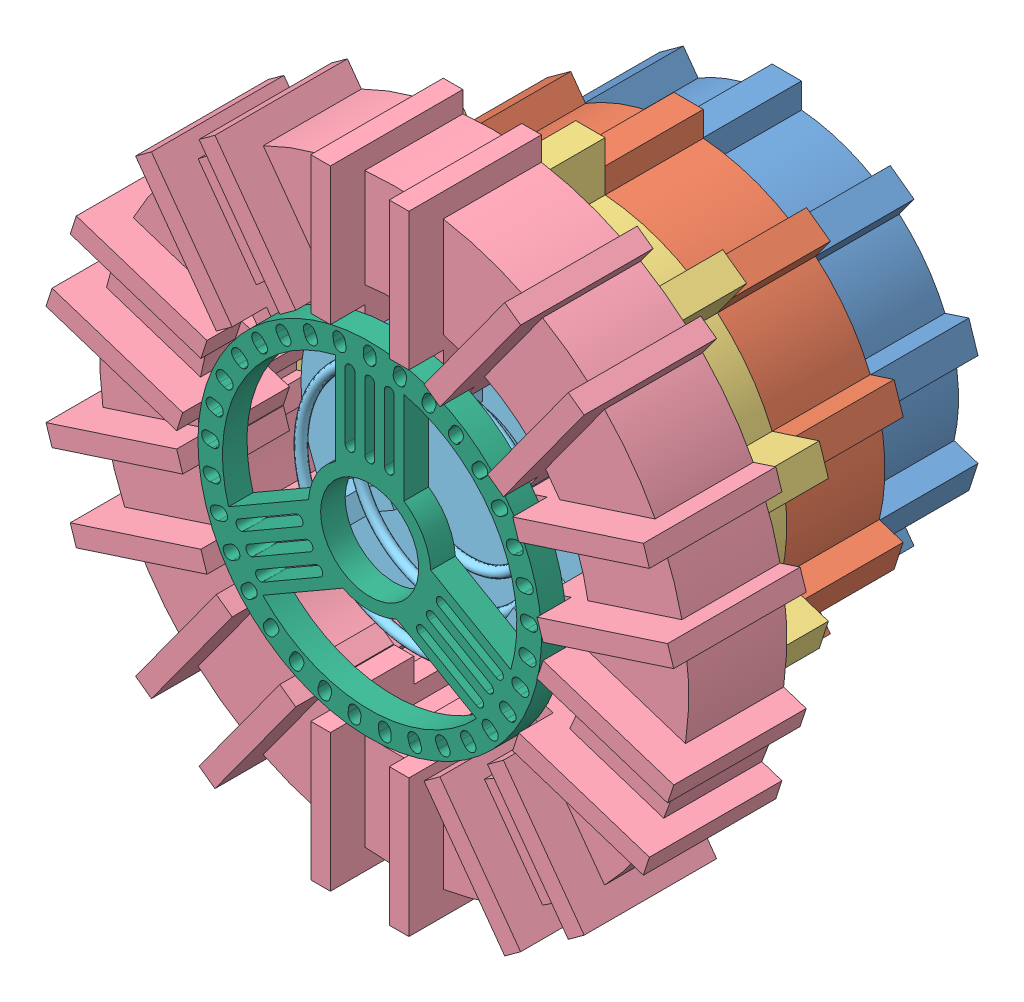
SolidWorks assembly 方舟装配体, configuration 默认. Lengths in mm.
Overall size (63.96 64 43.5).
53 component instances, 13 part files, 13 mates.
Components (placement in the parent):
- 底快3-1: 底快3 [默认] at (-8.2103 -2.3108 35) size (38.97 40 10)
- 散热块2-1: 散热块2 [默认] at (-8.2103 -2.3108 45) size (43.72 45 10)
- 散热块1-1: 散热块1 [默认] at (-8.2103 -2.3108 55) size (48.48 50 10)
- 外环-1: 外环 [默认] at (-7664.2063 -2380.1492 65) size (63.96 64 13.5)
- 金属环+底盘-1: 金属环+底盘 [默认] at (-8.2103 -2.3108 65) size (35 35 10)
- 内环-1: 内环 [默认] at (-8.2103 -2.3108 75) size (35 35 2.5)
- 方舟pcb3D图.step-1: 方舟pcb3D图.step [默认] at (-49.7173 -117.3506 55.4115) x (0.865992 0.500058 0) z (0 0 1) size (34.91 36 3.76)
  - Board.step-1: Board.step [默认] at origin size (34.91 36 0.41)
    - Open CASCADE STEP translator 6.8 1.1.1.step-1: Open CASCADE STEP translator 6.8 1.1.1.step [默认] at (0 0 -0.4115) size (34.91 36 0.41)
  - USB-MICRO_B.step-1: USB-MICRO_B.step [默认] at origin size (5.61 8.02 3.76)
    - USB_micro_A.step-1: USB_micro_A.step [默认] at (88.392 79.629 0) x (0 -1 0) z (0 0 1) size (8.02 5.61 3.76)
      - LOGO_.step-1: LOGO_.step [默认] at (-0.0055 0.0133 0.046) x (-1 0 0) z (0 0 -1) size (1.2 1.38 0.01)
      - USB_micro_A-0.step-1: USB_micro_A-0.step [默认] at origin size (8.02 5.61 3.76)
  - R5.step-1: R5.step [默认] at origin size (2 1.25 0.51)
    - R_0805.step-1: R_0805.step [默认] at (104.775 78.867 0) x (-1 0 0) z (0 0 1) size (2 1.25 0.51)
      - R_0805-1.step-1: R_0805-1.step [默认] at origin size (2 1.25 0.5)
      - LOGO_-2.step-1: LOGO_-2.step [默认] at (-0.0021 0.082 -0.003) x (-1 0 0) z (0 0 -1) size (0.9 1.04 0.01)
  - R4.step-1: R4.step [默认] at origin size (2.34 2.24 0.51)
    - R_0805.step-1: R_0805.step [默认] at (99.06 85.217 0) x (0.766044 -0.642788 0) z (0 0 1) size (2 1.25 0.51)
      - R_0805-1.step-1: R_0805-1.step [默认] at origin size (2 1.25 0.5)
      - LOGO_-2.step-1: LOGO_-2.step [默认] at (-0.0021 0.082 -0.003) x (-1 0 0) z (0 0 -1) size (0.9 1.04 0.01)
  - R3.step-1: R3.step [默认] at origin size (2.34 2.24 0.51)
    - R_0805.step-1: R_0805.step [默认] at (98.044 73.152 0) x (-0.766044 -0.642788 0) z (0 0 1) size (2 1.25 0.51)
      - R_0805-1.step-1: R_0805-1.step [默认] at origin size (2 1.25 0.5)
      - LOGO_-2.step-1: LOGO_-2.step [默认] at (-0.0021 0.082 -0.003) x (-1 0 0) z (0 0 -1) size (0.9 1.04 0.01)
  - R2.step-1: R2.step [默认] at origin size (2.08 2.36 0.51)
    - R_0805.step-1: R_0805.step [默认] at (87.249 89.662 0) x (0.5 -0.866025 0) z (0 0 1) size (2 1.25 0.51)
      - R_0805-1.step-1: R_0805-1.step [默认] at origin size (2 1.25 0.5)
      - LOGO_-2.step-1: LOGO_-2.step [默认] at (-0.0021 0.082 -0.003) x (-1 0 0) z (0 0 -1) size (0.9 1.04 0.01)
  - R1.step-1: R1.step [默认] at origin size (2.08 2.36 0.51)
    - R_0805.step-1: R_0805.step [默认] at (87.249 68.199 0) x (0.5 0.866025 0) z (0 0 1) size (2 1.25 0.51)
      - R_0805-1.step-1: R_0805-1.step [默认] at origin size (2 1.25 0.5)
      - LOGO_-2.step-1: LOGO_-2.step [默认] at (-0.0021 0.082 -0.003) x (-1 0 0) z (0 0 -1) size (0.9 1.04 0.01)
  - LED5.step-1: LED5.step [默认] at origin size (1.25 2 0.67)
    - LED_0805-G.step-1: LED_0805-G.step [默认] at (109.972 78.867 0) x (0 1 0) z (0 0 1) size (2 1.25 0.67)
      - LOGO_-3.step-1: LOGO_-3.step [默认] at (0 0.0303 -0.002) x (-1 0 0) z (0 0 -1) size (0.6 0.69 0)
      - LED_0805-G-4.step-1: LED_0805-G-4.step [默认] at origin size (2 1.25 0.67)
  - LED4.step-1: LED4.step [默认] at origin size (2.34 2.24 0.67)
    - LED_0805-G.step-1: LED_0805-G.step [默认] at (96.901 82.931 0) x (-0.766044 0.642788 0) z (0 0 1) size (2 1.25 0.67)
      - LOGO_-3.step-1: LOGO_-3.step [默认] at (0 0.0303 -0.002) x (-1 0 0) z (0 0 -1) size (0.6 0.69 0)
      - LED_0805-G-4.step-1: LED_0805-G-4.step [默认] at origin size (2 1.25 0.67)
  - LED3.step-1: LED3.step [默认] at origin size (2.34 2.24 0.67)
    - LED_0805-G.step-1: LED_0805-G.step [默认] at (96.266 75.057 0) x (-0.766044 -0.642788 0) z (0 0 1) size (2 1.25 0.67)
      - LOGO_-3.step-1: LOGO_-3.step [默认] at (0 0.0303 -0.002) x (-1 0 0) z (0 0 -1) size (0.6 0.69 0)
      - LED_0805-G-4.step-1: LED_0805-G-4.step [默认] at origin size (2 1.25 0.67)
  - LED2.step-1: LED2.step [默认] at origin size (2.36 2.08 0.67)
    - LED_0805-G.step-1: LED_0805-G.step [默认] at (85.725 93.345 0) x (0.866025 0.5 0) z (0 0 1) size (2 1.25 0.67)
      - LOGO_-3.step-1: LOGO_-3.step [默认] at (0 0.0303 -0.002) x (-1 0 0) z (0 0 -1) size (0.6 0.69 0)
      - LED_0805-G-4.step-1: LED_0805-G-4.step [默认] at origin size (2 1.25 0.67)
  - LED1.step-1: LED1.step [默认] at origin size (2.36 2.08 0.67)
    - LED_0805-G.step-1: LED_0805-G.step [默认] at (85.09 64.77 0) x (0.866025 -0.5 0) z (0 0 1) size (2 1.25 0.67)
      - LOGO_-3.step-1: LOGO_-3.step [默认] at (0 0.0303 -0.002) x (-1 0 0) z (0 0 -1) size (0.6 0.69 0)
      - LED_0805-G-4.step-1: LED_0805-G-4.step [默认] at origin size (2 1.25 0.67)
Mates (geometry in assembly coordinates):
- 重合1: coincident anti-aligned: plane of 底快3-1 through (-8.2103 -2.3108 45) normal (0 0 1); plane of 散热块2-1 through (-8.2103 -2.3108 45) normal (0 0 -1)
- 同心1: concentric aligned: circle of 底快3-1; circle of 散热块2-1
- 重合2: coincident anti-aligned: plane of 散热块2-1 through (-8.2103 -2.3108 55) normal (0 0 1); plane of 散热块1-1 through (-8.2103 -2.3108 55) normal (0 0 -1)
- 同心2: concentric aligned: circle of 散热块2-1; circle of 散热块1-1
- 重合3: coincident anti-aligned: plane of 散热块1-1 through (-8.2103 -2.3108 65) normal (0 0 1); plane of 外环-1 through (-7664.2063 -2380.1492 65) normal (0 0 -1)
- 同心3: concentric aligned: circle of 散热块2-1; circle of 外环-1
- 重合4: coincident anti-aligned: plane of 散热块1-1 through (-8.2103 -2.3108 65) normal (0 0 1); plane of 金属环+底盘-1 through (-8.2103 -2.3108 65) normal (0 0 -1)
- 同心4: concentric aligned: circle of 散热块1-1; circle of 金属环+底盘-1
- 重合5: coincident anti-aligned: plane of 外环-1 through (4.7969 -15.1098 75) normal (0 0 1); plane of 内环-1 through (-8.2103 -2.3108 75) normal (0 0 -1)
- 同心5: concentric aligned: circle of 底快3-1; circle of 内环-1
- 重合6: coincident aligned: plane of 散热块1-1 through (-8.2103 -2.3108 55) normal (0 0 -1); plane of 方舟pcb3D图.step-1/Board.step-1/Open CASCADE STEP translator 6.8 1.1.1.step-1 through (-19.7784 -16.1001 55) normal (0 0 -1)
- 同心7: concentric anti-aligned: circle of 底快3-1; circle of 方舟pcb3D图.step-1/Board.step-1/Open CASCADE STEP translator 6.8 1.1.1.step-1
- 重合7: coincident anti-aligned: line of 散热块1-1 through (-2.0539 14.6036 55) axis (-0.34202 -0.939693 0); line of 方舟pcb3D图.step-1/Board.step-1/Open CASCADE STEP translator 6.8 1.1.1.step-1 through (-3.0798 11.785 55) axis (0.34202 0.939693 0)
